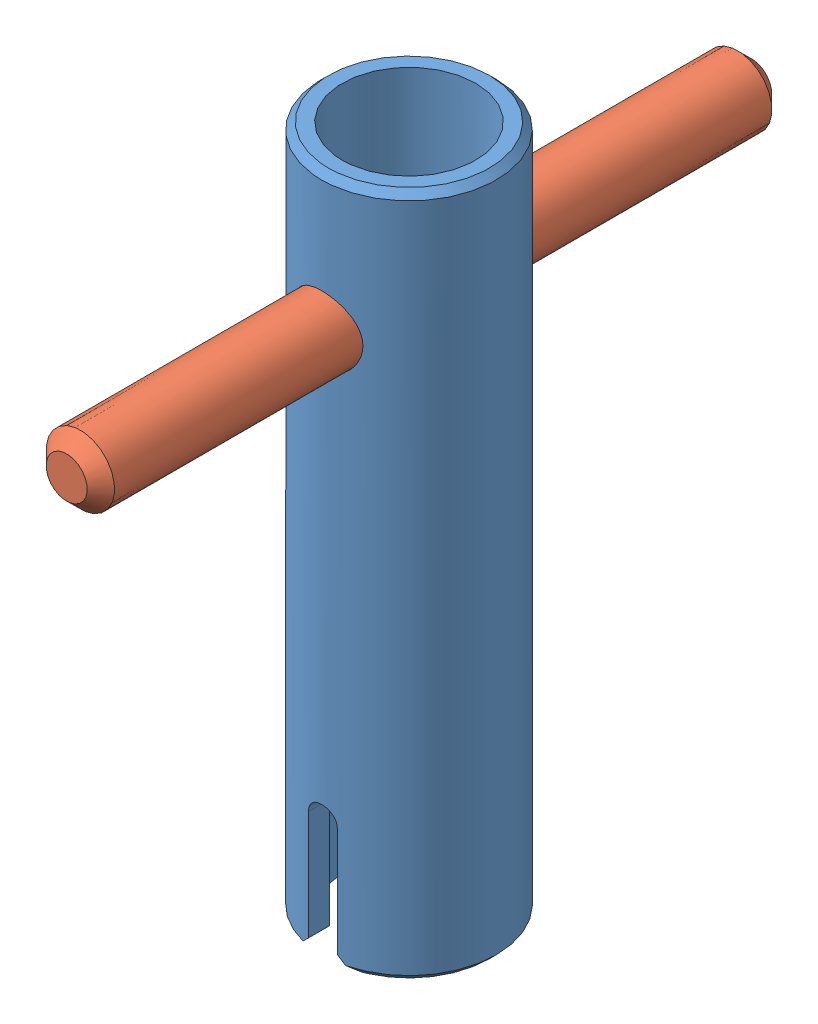
SolidWorks assembly BNC_panel_mount_tool_v1.0, configuration Default. Lengths in mm.
Overall size (12.75 50 50).
2 component instances, 2 part files, 2 mates.
Components (placement in the parent):
- BNC_panel_mount_tool_head_v1.0-1: BNC_panel_mount_tool_head_v1.0 [Default] at (-83.1378 -9.8127 33.5527) size (12.75 50 12.75)
- BNC_panel_mount_tool_handle_v1.0-1: BNC_panel_mount_tool_handle_v1.0 [Default] at (-83.1378 30.1873 58.5527) x (0.993448 -0.114287 0) z (0.114287 0.993448 0) size (5 50 5)
Mates (geometry in assembly coordinates):
- Concentric1: concentric anti-aligned: cylinder of BNC_panel_mount_tool_head_v1.0-1 through (-83.1378 30.1873 39.9277) axis (0 0 -1) radius 2.5; cylinder of BNC_panel_mount_tool_handle_v1.0-1 through (-83.1378 30.1873 8.5527) axis (0 0 1) radius 2.5
- Coincident1: coincident anti-aligned: plane of BNC_panel_mount_tool_head_v1.0-1 through (-83.1378 -9.8127 33.5527) normal (0 0 1); plane of BNC_panel_mount_tool_handle_v1.0-1
